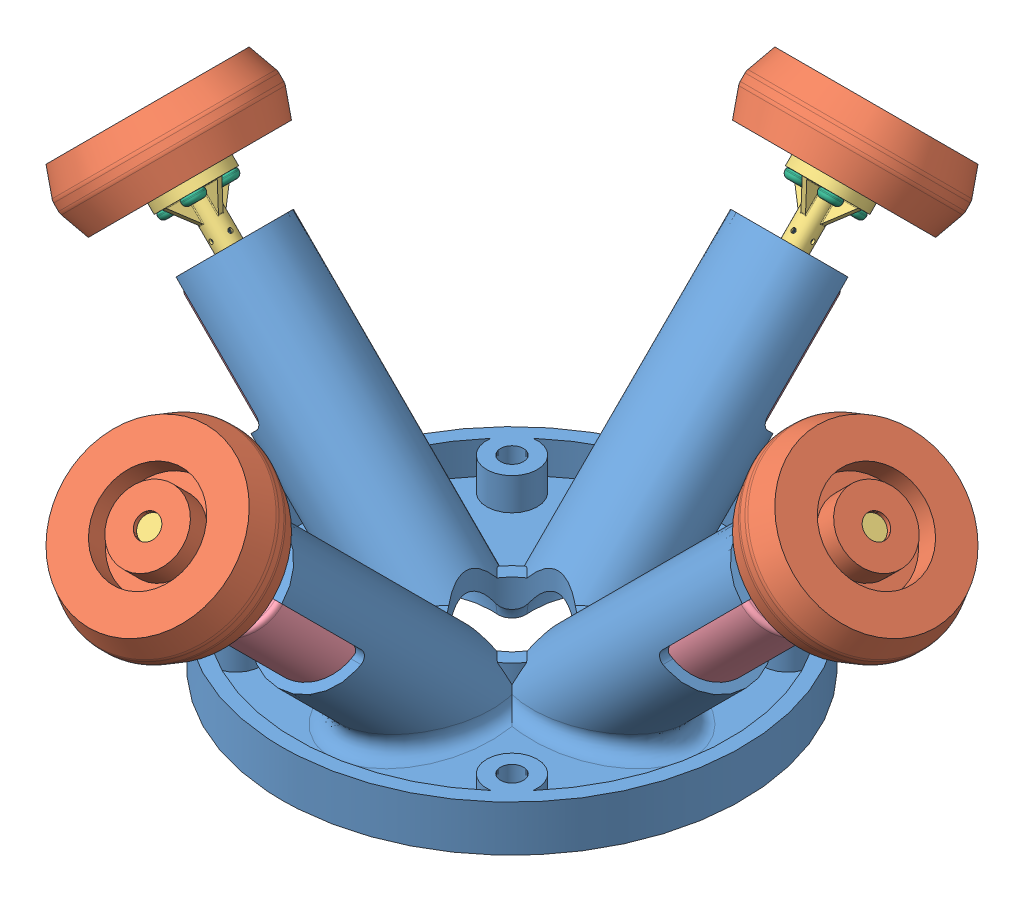
SolidWorks assembly FourLegASM, configuration Default. Lengths in mm.
Overall size (237.13 102.02 237.13).
49 component instances, 6 part files, 2 mates.
Components (placement in the parent):
- FourLegBase-1: FourLegBase [Default] at (33.0096 39.469 80.9309) size (156.3 71.93 156.3)
- MotorWheelASM-1: MotorWheelASM [Default] at (114.1265 63.6133 80.3682) x (0 0 -1) z (0.707107 0.707107 0) size (50.8 50.8 69.16)
  - Omni_Wheel-1: Omni_Wheel [Default] at (-0.5626 28.5849 47.8869) size (50.8 50.8 16.51)
  - MotorWheelCoupler-1: MotorWheelCoupler [Default] at (-0.5626 28.5849 37.0919) size (19.05 19.05 30.48)
  - DC_Motor-1: DC_Motor [Default] at (-0.5626 28.5849 -8.9583) size (24.38 24.38 45.03)
  - 92311A050_18-8 SS CUP POINT SET SCREW-1: 92311A050_18-8 SS CUP POINT SET SCREW [92311A050] at (-2.3871 28.5849 26.9319) x (0 0 1) z (-1 0 0) size (1.76 1.55 1.71)
  - 92311A050_18-8 SS CUP POINT SET SCREW-2: 92311A050_18-8 SS CUP POINT SET SCREW [92311A050] at (-0.5626 26.7604 26.9319) x (0 0 1) z (0 -1 0) size (1.76 1.55 1.71)
  - 92311A050_18-8 SS CUP POINT SET SCREW-3: 92311A050_18-8 SS CUP POINT SET SCREW [92311A050] at (1.2619 28.5849 26.9319) x (0 0 1) z (1 0 0) size (1.76 1.55 1.71)
  - 92311A050_18-8 SS CUP POINT SET SCREW-4: 92311A050_18-8 SS CUP POINT SET SCREW [92311A050] at (-0.5626 30.4094 26.9319) x (0 0 1) z (0 1 0) size (1.76 1.55 1.71)
  - 94629A550_THREAD-CUTTING SCREW FOR SOFT PLASTICS-1: 94629A550_THREAD-CUTTING SCREW FOR SOFT PLASTICS [94629A550] at (4.0094 24.0129 37.0919) x (-0.923728 -0.383049 0) z (0 0 -1) size (5.56 5.82 14.35)
  - 94629A550_THREAD-CUTTING SCREW FOR SOFT PLASTICS-2: 94629A550_THREAD-CUTTING SCREW FOR SOFT PLASTICS [94629A550] at (4.0094 33.1569 37.0919) x (0.383049 -0.923728 0) z (0 0 -1) size (5.56 5.82 14.35)
  - 94629A550_THREAD-CUTTING SCREW FOR SOFT PLASTICS-3: 94629A550_THREAD-CUTTING SCREW FOR SOFT PLASTICS [94629A550] at (-5.1346 33.1569 37.0919) x (0.923728 0.383049 0) z (0 0 -1) size (5.56 5.82 14.35)
  - 94629A550_THREAD-CUTTING SCREW FOR SOFT PLASTICS-4: 94629A550_THREAD-CUTTING SCREW FOR SOFT PLASTICS [94629A550] at (-5.1346 24.0129 37.0919) x (-0.383049 0.923728 0) z (0 0 -1) size (5.56 5.82 14.35)
- MotorWheelASM-2: MotorWheelASM [Default] at (33.5723 63.6133 162.0477) x (1 0 0) z (0 0.707107 0.707107) size (50.8 50.8 69.16)
  - Omni_Wheel-1: Omni_Wheel [Default] at (-0.5626 28.5849 47.8869) size (50.8 50.8 16.51)
  - MotorWheelCoupler-1: MotorWheelCoupler [Default] at (-0.5626 28.5849 37.0919) size (19.05 19.05 30.48)
  - DC_Motor-1: DC_Motor [Default] at (-0.5626 28.5849 -8.9583) size (24.38 24.38 45.03)
  - 92311A050_18-8 SS CUP POINT SET SCREW-1: 92311A050_18-8 SS CUP POINT SET SCREW [92311A050] at (-2.3871 28.5849 26.9319) x (0 0 1) z (-1 0 0) size (1.76 1.55 1.71)
  - 92311A050_18-8 SS CUP POINT SET SCREW-2: 92311A050_18-8 SS CUP POINT SET SCREW [92311A050] at (-0.5626 26.7604 26.9319) x (0 0 1) z (0 -1 0) size (1.76 1.55 1.71)
  - 92311A050_18-8 SS CUP POINT SET SCREW-3: 92311A050_18-8 SS CUP POINT SET SCREW [92311A050] at (1.2619 28.5849 26.9319) x (0 0 1) z (1 0 0) size (1.76 1.55 1.71)
  - 92311A050_18-8 SS CUP POINT SET SCREW-4: 92311A050_18-8 SS CUP POINT SET SCREW [92311A050] at (-0.5626 30.4094 26.9319) x (0 0 1) z (0 1 0) size (1.76 1.55 1.71)
  - 94629A550_THREAD-CUTTING SCREW FOR SOFT PLASTICS-1: 94629A550_THREAD-CUTTING SCREW FOR SOFT PLASTICS [94629A550] at (4.0094 24.0129 37.0919) x (-0.923728 -0.383049 0) z (0 0 -1) size (5.56 5.82 14.35)
  - 94629A550_THREAD-CUTTING SCREW FOR SOFT PLASTICS-2: 94629A550_THREAD-CUTTING SCREW FOR SOFT PLASTICS [94629A550] at (4.0094 33.1569 37.0919) x (0.383049 -0.923728 0) z (0 0 -1) size (5.56 5.82 14.35)
  - 94629A550_THREAD-CUTTING SCREW FOR SOFT PLASTICS-3: 94629A550_THREAD-CUTTING SCREW FOR SOFT PLASTICS [94629A550] at (-5.1346 33.1569 37.0919) x (0.923728 0.383049 0) z (0 0 -1) size (5.56 5.82 14.35)
  - 94629A550_THREAD-CUTTING SCREW FOR SOFT PLASTICS-4: 94629A550_THREAD-CUTTING SCREW FOR SOFT PLASTICS [94629A550] at (-5.1346 24.0129 37.0919) x (-0.383049 0.923728 0) z (0 0 -1) size (5.56 5.82 14.35)
- MotorWheelASM-3: MotorWheelASM [Default] at (-48.1072 63.6133 81.4935) x (0 0 1) z (-0.707107 0.707107 0) size (50.8 50.8 69.16)
  - Omni_Wheel-1: Omni_Wheel [Default] at (-0.5626 28.5849 47.8869) size (50.8 50.8 16.51)
  - MotorWheelCoupler-1: MotorWheelCoupler [Default] at (-0.5626 28.5849 37.0919) size (19.05 19.05 30.48)
  - DC_Motor-1: DC_Motor [Default] at (-0.5626 28.5849 -8.9583) size (24.38 24.38 45.03)
  - 92311A050_18-8 SS CUP POINT SET SCREW-1: 92311A050_18-8 SS CUP POINT SET SCREW [92311A050] at (-2.3871 28.5849 26.9319) x (0 0 1) z (-1 0 0) size (1.76 1.55 1.71)
  - 92311A050_18-8 SS CUP POINT SET SCREW-2: 92311A050_18-8 SS CUP POINT SET SCREW [92311A050] at (-0.5626 26.7604 26.9319) x (0 0 1) z (0 -1 0) size (1.76 1.55 1.71)
  - 92311A050_18-8 SS CUP POINT SET SCREW-3: 92311A050_18-8 SS CUP POINT SET SCREW [92311A050] at (1.2619 28.5849 26.9319) x (0 0 1) z (1 0 0) size (1.76 1.55 1.71)
  - 92311A050_18-8 SS CUP POINT SET SCREW-4: 92311A050_18-8 SS CUP POINT SET SCREW [92311A050] at (-0.5626 30.4094 26.9319) x (0 0 1) z (0 1 0) size (1.76 1.55 1.71)
  - 94629A550_THREAD-CUTTING SCREW FOR SOFT PLASTICS-1: 94629A550_THREAD-CUTTING SCREW FOR SOFT PLASTICS [94629A550] at (4.0094 24.0129 37.0919) x (-0.923728 -0.383049 0) z (0 0 -1) size (5.56 5.82 14.35)
  - 94629A550_THREAD-CUTTING SCREW FOR SOFT PLASTICS-2: 94629A550_THREAD-CUTTING SCREW FOR SOFT PLASTICS [94629A550] at (4.0094 33.1569 37.0919) x (0.383049 -0.923728 0) z (0 0 -1) size (5.56 5.82 14.35)
  - 94629A550_THREAD-CUTTING SCREW FOR SOFT PLASTICS-3: 94629A550_THREAD-CUTTING SCREW FOR SOFT PLASTICS [94629A550] at (-5.1346 33.1569 37.0919) x (0.923728 0.383049 0) z (0 0 -1) size (5.56 5.82 14.35)
  - 94629A550_THREAD-CUTTING SCREW FOR SOFT PLASTICS-4: 94629A550_THREAD-CUTTING SCREW FOR SOFT PLASTICS [94629A550] at (-5.1346 24.0129 37.0919) x (-0.383049 0.923728 0) z (0 0 -1) size (5.56 5.82 14.35)
- MotorWheelASM-4: MotorWheelASM [Default] at (32.447 63.6133 -0.186) x (-1 0 0) z (0 0.707107 -0.707107) size (50.8 50.8 69.16)
  - Omni_Wheel-1: Omni_Wheel [Default] at (-0.5626 28.5849 47.8869) size (50.8 50.8 16.51)
  - MotorWheelCoupler-1: MotorWheelCoupler [Default] at (-0.5626 28.5849 37.0919) size (19.05 19.05 30.48)
  - DC_Motor-1: DC_Motor [Default] at (-0.5626 28.5849 -8.9583) size (24.38 24.38 45.03)
  - 92311A050_18-8 SS CUP POINT SET SCREW-1: 92311A050_18-8 SS CUP POINT SET SCREW [92311A050] at (-2.3871 28.5849 26.9319) x (0 0 1) z (-1 0 0) size (1.76 1.55 1.71)
  - 92311A050_18-8 SS CUP POINT SET SCREW-2: 92311A050_18-8 SS CUP POINT SET SCREW [92311A050] at (-0.5626 26.7604 26.9319) x (0 0 1) z (0 -1 0) size (1.76 1.55 1.71)
  - 92311A050_18-8 SS CUP POINT SET SCREW-3: 92311A050_18-8 SS CUP POINT SET SCREW [92311A050] at (1.2619 28.5849 26.9319) x (0 0 1) z (1 0 0) size (1.76 1.55 1.71)
  - 92311A050_18-8 SS CUP POINT SET SCREW-4: 92311A050_18-8 SS CUP POINT SET SCREW [92311A050] at (-0.5626 30.4094 26.9319) x (0 0 1) z (0 1 0) size (1.76 1.55 1.71)
  - 94629A550_THREAD-CUTTING SCREW FOR SOFT PLASTICS-1: 94629A550_THREAD-CUTTING SCREW FOR SOFT PLASTICS [94629A550] at (4.0094 24.0129 37.0919) x (-0.923728 -0.383049 0) z (0 0 -1) size (5.56 5.82 14.35)
  - 94629A550_THREAD-CUTTING SCREW FOR SOFT PLASTICS-2: 94629A550_THREAD-CUTTING SCREW FOR SOFT PLASTICS [94629A550] at (4.0094 33.1569 37.0919) x (0.383049 -0.923728 0) z (0 0 -1) size (5.56 5.82 14.35)
  - 94629A550_THREAD-CUTTING SCREW FOR SOFT PLASTICS-3: 94629A550_THREAD-CUTTING SCREW FOR SOFT PLASTICS [94629A550] at (-5.1346 33.1569 37.0919) x (0.923728 0.383049 0) z (0 0 -1) size (5.56 5.82 14.35)
  - 94629A550_THREAD-CUTTING SCREW FOR SOFT PLASTICS-4: 94629A550_THREAD-CUTTING SCREW FOR SOFT PLASTICS [94629A550] at (-5.1346 24.0129 37.0919) x (-0.383049 0.923728 0) z (0 0 -1) size (5.56 5.82 14.35)
Mates (geometry in assembly coordinates):
- Concentric1: concentric aligned: cylinder of FourLegBase-1 through (109.3655 99.2775 80.9309) axis (-0.707107 -0.707107 0) radius 12.1285; cylinder of MotorWheelASM-1/DC_Motor-1 through (109.3655 99.2775 80.9309) axis (-0.707107 -0.707107 0) radius 12.192
- Coincident1: coincident anti-aligned: plane of FourLegBase-1 through (109.3655 99.2775 80.9309) normal (-0.707107 -0.707107 0); plane of MotorWheelASM-1/DC_Motor-1 through (109.3655 99.2775 80.9309) normal (0.707107 0.707107 0)
